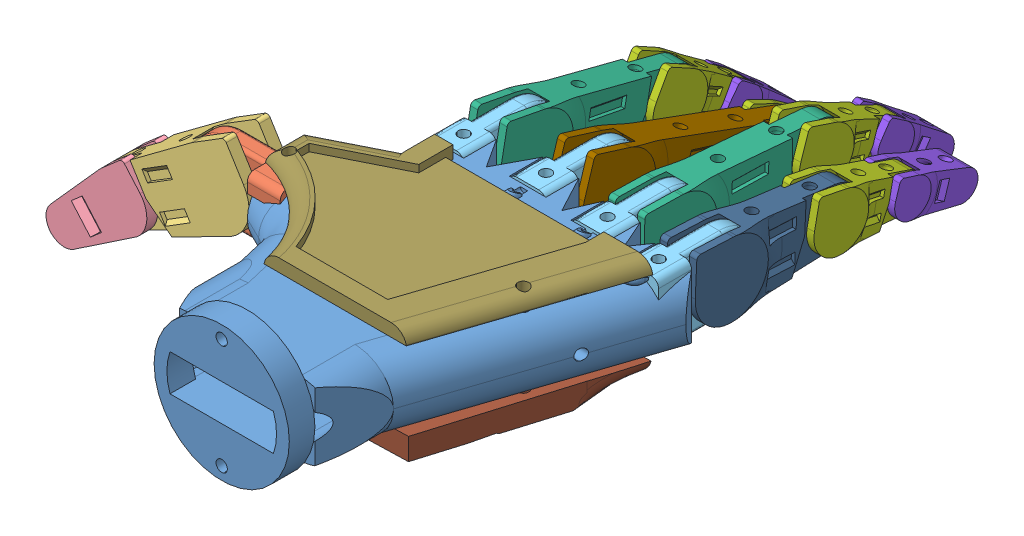
SolidWorks assembly ASSIEME_MANO, configuration Default. Lengths in mm.
Overall size (145.26 57.62 186.88).
27 component instances, 12 part files, 24 mates.
Components (placement in the parent):
- rh palm-2: rh palm [Default] at (38.6924 45.2252 58.7428) size (86 37 93)
- rh4v4-1: rh4v4 [Default] at (9.0148 35.3337 79.9649) x (-1 0 0) z (0 0 -1) size (69.26 51.67 15) (flexible)
  - robot hand v4 f4 4-1: robot hand v4 f4 4 [Default] at (21.3224 10.6534 23.7221) size (30 20 15)
  - rhf4l1-1: rhf4l1 [Default] at (34.0629 2.7363 23.7221) x (0.849367 -0.527802 0) z (0 0 1) size (47.5 20 12)
  - rhf4l2-1: rhf4l2 [Default] at (54.3473 -11.745 23.7221) x (0.754389 -0.656428 0) z (0 0 1) size (32.5 15 12)
- rh1f1 v4-1: rh1f1 v4 [Default] at (-8.7956 53.4364 26.4661) x (0 -1 0) z (1 0 0) size (25.45 99.09 12) (flexible)
  - robot hand v4 f1 4-1: robot hand v4 f1 4 [Default] at (7.4493 16.7233 27.6774) x (0 1 0) z (0 0 1) size (30 20 10)
  - rhf1l1-1: rhf1l1 [Default] at (11.2139 36.3658 27.6774) x (0.188227 0.982125 0) z (0 0 1) size (57.5 21.9 12)
  - rhf1l2-1: rhf1l2 [Default] at (19.7973 64.7707 27.6774) x (0.481885 0.876235 0) z (0 0 1) size (32.5 16.23 12)
  - rhf1l3-1: rhf1l3 [Default] at (29.1416 79.5138 27.6774) x (0.603401 0.797438 0) z (0 0 1) size (24 10.94 11)
- rh1f2 v4-1: rh1f2 v4 [Default] at (11.7208 53.4364 24.4661) x (0 -1 0) z (1 0 0) size (53.34 103.88 12) (flexible)
  - robot hand v4 f1 4-1: robot hand v4 f1 4 [Default] at (7.4493 16.7233 27.6774) x (0 1 0) z (0 0 1) size (30 20 10)
  - rhf2l1-1: rhf2l1 [Default] at (14.8673 40.5974 27.6774) x (0.296719 0.954965 0) z (0 0 1) size (67.5 21.94 12)
  - rhf1l2-1: rhf1l2 [Default] at (26.6507 73.4683 27.6774) x (0.43655 0.89968 0) z (0 0 1) size (32.5 16.23 12)
  - rhf1l3-1: rhf1l3 [Default] at (35.7947 88.2458 27.6774) x (0.63713 0.770756 0) z (0 0 1) size (24 10.94 11)
- rh1f3 v4-1: rh1f3 v4 [Default] at (47.5443 53.4364 29.4661) x (0 -1 0) z (1 0 0) size (28.08 89.33 12.34) (flexible)
  - robot hand v4 f1 4-1: robot hand v4 f1 4 [Default] at (7.4493 16.7233 27.6774) x (0 1 0) z (0 0 1) size (30 20 10)
  - rhf3l1-1: rhf3l1 [Default] at (8.1487 31.707 27.6774) x (0.046624 0.998913 0) z (0 0 1) size (47.5 21.81 12.12)
  - rhf1l2-1: rhf1l2 [Default] at (10.8569 56.4868 27.6774) x (0.200882 0.979615 0) z (0 0 1) size (32.5 16.23 12)
  - rhf1l3-1: rhf1l3 [Default] at (15.1158 73.4375 27.6774) x (0.300013 0.953935 0) z (0 0 1) size (24 10.94 11)
- rh1f1 v4-2: rh1f1 v4 [Default] at (30.5607 53.4364 26.4661) x (0 -1 0) z (1 0 0) size (25.45 99.09 12) (flexible)
  - robot hand v4 f1 4-1: robot hand v4 f1 4 [Default] at (7.4493 16.7233 27.6774) x (0 1 0) z (0 0 1) size (30 20 10)
  - rhf1l1-1: rhf1l1 [Default] at (7.9021 36.7182 27.6774) x (0.02264 0.999744 0) z (0 0 1) size (57.5 21.9 12)
  - rhf1l2-1: rhf1l2 [Default] at (11.5203 66.1988 27.6774) x (0.316536 0.948581 0) z (0 0 1) size (32.5 16.23 12)
  - rhf1l3-1: rhf1l3 [Default] at (18.9031 81.8865 27.6774) x (0.562324 0.826917 0) z (0 0 1) size (24 10.94 11)
- rh palmcover2-1: rh palmcover2 [Default] at (-59.598 42.2252 62.3331) x (0.999596 0 -0.028409) z (0.028409 0 0.999596) size (79.56 7.01 50.59)
- rh palmcover1-1: rh palmcover1 [Default] at (38.6924 69.6868 58.7428) size (79.72 4.01 50.59)
Mates (geometry in assembly coordinates):
- Coincident1: coincident anti-aligned: plane of rh palm-2 through (38.6924 51.2252 58.7428) normal (0 1 0); plane of rh4v4-1/robot hand v4 f4 4-1 through (7.6924 51.2252 48.7428) normal (0 -1 0)
- Coincident2: coincident anti-aligned: plane of rh palm-2 through (-12.3076 45.2252 53.7428) normal (0 0 1); plane of rh4v4-1/robot hand v4 f4 4-1 through (-12.3076 45.9871 53.7428) normal (0 0 -1)
- Coincident3: coincident anti-aligned: plane of rh palm-2 through (7.6924 51.2252 48.7447) normal (-1 0 0); plane of rh4v4-1/robot hand v4 f4 4-1 through (7.6924 55.9871 53.7428) normal (1 0 0)
- Coincident4: coincident anti-aligned: plane of rh palm-2 through (72.7217 45.2252 12.7428) normal (1 0 0); plane of rh1f3 v4-1/robot hand v4 f1 4-1 through (72.7217 45.9871 12.7428) normal (-1 0 0)
- Coincident5: coincident anti-aligned: plane of rh palm-2 through (38.6924 51.2252 58.7428) normal (0 1 0); plane of rh1f3 v4-1/robot hand v4 f1 4-1 through (80.2217 51.2252 32.7428) normal (0 -1 0)
- Coincident6: coincident anti-aligned: plane of rh palm-2 through (70.2217 51.2252 32.7428) normal (0 0 -1); plane of rh1f3 v4-1/robot hand v4 f1 4-1 through (77.7217 55.9871 32.7428) normal (0 0 1)
- Coincident7: coincident anti-aligned: plane of rh palm-2 through (34.3982 51.2252 27.7428) normal (0 0 -1); plane of rh1f2 v4-1/robot hand v4 f1 4-1 through (41.8982 55.9871 27.7428) normal (0 0 1)
- Coincident8: coincident anti-aligned: plane of rh palm-2 through (41.8982 45.2252 7.7428) normal (-1 0 0); plane of rh1f2 v4-1/robot hand v4 f1 4-1 through (41.8982 45.9871 7.7428) normal (1 0 0)
- Coincident10: coincident anti-aligned: plane of rh palm-2 through (60.7381 45.2252 9.7428) normal (-1 0 0); plane of rh1f1 v4-2/robot hand v4 f1 4-1 through (60.7381 45.9871 9.7428) normal (1 0 0)
- Coincident11: coincident anti-aligned: plane of rh palm-2 through (38.6924 51.2252 58.7428) normal (0 1 0); plane of rh1f1 v4-2/robot hand v4 f1 4-1 through (63.2381 51.2252 29.7428) normal (0 -1 0)
- Coincident12: coincident anti-aligned: plane of rh palm-2 through (53.2381 51.2252 29.7428) normal (0 0 -1); plane of rh1f1 v4-2/robot hand v4 f1 4-1 through (60.7381 55.9871 29.7428) normal (0 0 1)
- Coincident13: coincident anti-aligned: plane of rh palm-2 through (16.3818 45.2252 9.7428) normal (1 0 0); plane of rh1f1 v4-1/robot hand v4 f1 4-1 through (16.3818 45.9871 9.7428) normal (-1 0 0)
- Coincident14: coincident anti-aligned: plane of rh palm-2 through (38.6924 51.2252 58.7428) normal (0 1 0); plane of rh1f1 v4-1/robot hand v4 f1 4-1 through (23.8818 51.2252 29.7428) normal (0 -1 0)
- Coincident15: coincident anti-aligned: plane of rh palm-2 through (13.8818 51.2252 29.7428) normal (0 0 -1); plane of rh1f1 v4-1/robot hand v4 f1 4-1 through (21.3818 55.9871 29.7428) normal (0 0 1)
- Coincident16: coincident anti-aligned: plane of rh palm-2 through (38.6924 51.2252 58.7428) normal (0 1 0); plane of rh1f2 v4-1/robot hand v4 f1 4-1 through (44.3982 51.2252 27.7428) normal (0 -1 0)
- Coincident17: coincident anti-aligned: plane of rh palm-2 through (23.9685 40.2252 78.7428) normal (0 1 0); plane of rh fav4-1 through (21.6028 40.2252 88.7428) normal (0 -1 0)
- Concentric1: concentric aligned: cylinder of rh palm-2 through (21.6028 45.2252 78.7428) axis (0 0 1) radius 4.7314; cylinder of rh fav4-1 through (21.6028 45.2252 88.7428) axis (0 0 1) radius 5
- Coincident18: coincident anti-aligned: plane of rh palm-2 through (23.9685 45.2252 103.7428) normal (0 0 1); plane of rh fav4-1 through (21.6028 45.2252 103.7428) normal (0 0 -1)
- Coincident19: coincident anti-aligned: plane of rh fav4-1 through (37.3778 55.2252 283.7428) normal (0 0 1); plane of rh fav5-1 through (-8.3972 55.2252 283.7428) normal (0 0 -1)
- Coincident20: coincident anti-aligned: line of rh fav4-1 through (-8.3972 45.2252 283.7428) axis (0 1 0); line of rh fav5-1 through (-8.3972 55.2252 283.7428) axis (0 -1 0)
- Coincident23: coincident anti-aligned: line of rh fav4-1 through (-8.3972 45.2252 283.7428) axis (1 0 0); line of rh fav5-1 through (87.6028 45.2252 283.7428) axis (-1 0 0)
- Coincident54: coincident anti-aligned: plane of rh palm-2 through (38.6924 35.2252 58.7428) normal (0 -1 0); plane of rh palmcover2-1 through (-8.5328 35.2252 92.9361) normal (0 1 0)
- Concentric21: concentric aligned: cylinder of rh palm-2 through (66.6924 55.2252 56.2428) axis (0 -1 0) radius 1.5; cylinder of rh palmcover2-1 through (66.6924 35.2252 56.2428) axis (0 -1 0) radius 1.5
- Concentric22: concentric aligned: cylinder of rh4v4-1/robot hand v4 f4 4-1 through (2.6924 35.9871 56.2428) axis (0 1 0) radius 1.5; cylinder of rh palmcover1-1 through (2.6924 49.6868 56.2428) axis (0 1 0) radius 1.5
